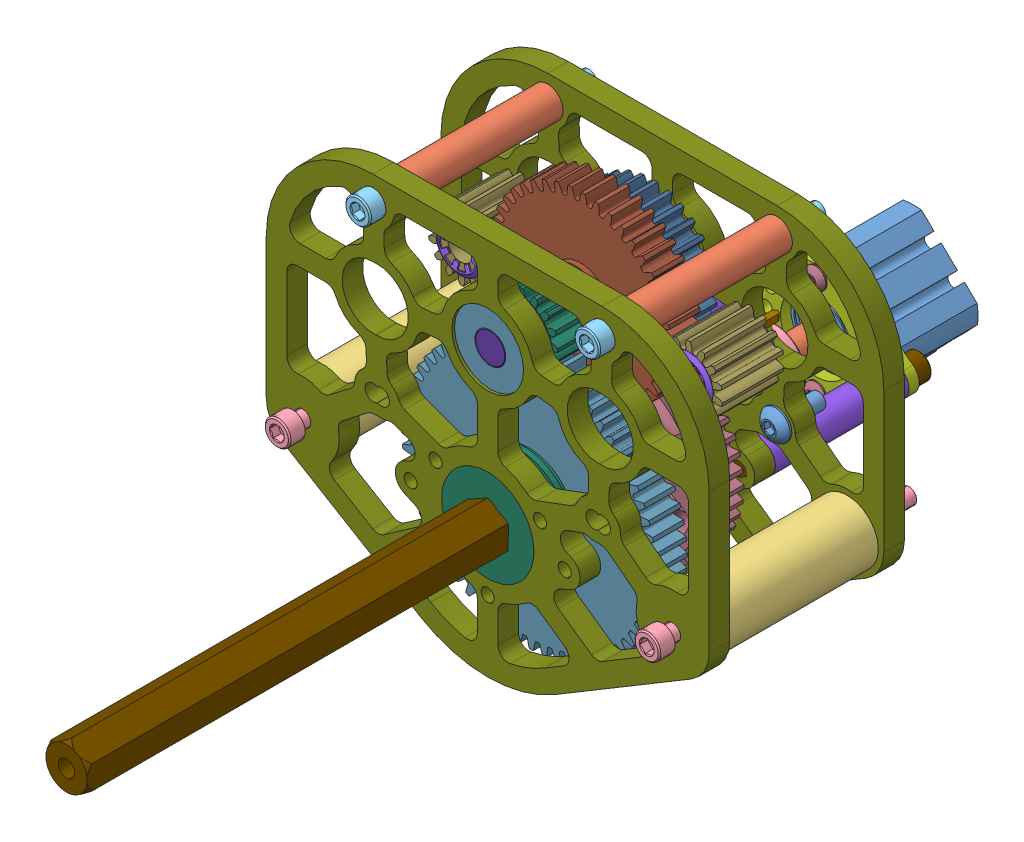
SolidWorks assembly 217-3423-STEP, configuration Default. Lengths in mm.
Overall size (138.74 141.15 261.84).
65 component instances, 41 part files, 0 mates.
Components (placement in the parent):
- 217-2778-001 Rev2_NCQ8A075-050M-1: 217-2778-001 Rev2_NCQ8A075-050M [Default] at (0 -47.0408 -61.087) x (-0.724709 0.689055 0) z (0 0 1) size (31.75 33.34 52.54)
  - 217-2778-NCQ8A075-050M_NCQ8 Tube_075A-1: 217-2778-NCQ8A075-050M_NCQ8 Tube_075A [Default] at origin size (31.75 33.34 26.92)
  - 217-2778-NCQ8A075-050M_NCQ8 Rod_075M-1: 217-2778-NCQ8A075-050M_NCQ8 Rod_075M [Default] at (0 0 3.8126) x (-1 0 0) z (0 0 1) size (18.95 18.95 35.27)
  - 217-2778-NCQ8A075-050M_Snap Ring_075-1: 217-2778-NCQ8A075-050M_Snap Ring_075 [Default] at (0 0 10.362) size (21 20.74 0.97)
- 217-3195-200 Rev1-1: 217-3195-200 Rev1 [Default] at (0 -47.0408 -22.8339) x (1 0 0) z (0 0 -1) size (20.44 19.56 22.68)
  - 217-3195-010 Rev1-1: 217-3195-010 Rev1 [Default] x (-1 0 0) z (0 0 1) size (19.61 11.78 22.68)
  - 217-3195-010 Rev1-2: 217-3195-010 Rev1 [Default] at origin size (19.61 11.78 22.68)
  - 217-2778-NCQ8A075-050M_1032_Nut_90545A111-1: 217-2778-NCQ8A075-050M_1032_Nut_90545A111 [Default] at (0 0 2.5527) x (-0.5 0.866025 0) z (0 0 1) size (9.53 11 3.39)
  - 91251A107_91251A107-1: 91251A107_91251A107 [Default] at (-7.4168 -4.9375 -0.635) x (1 0 0) z (0 -1 0) size (4.65 4.65 10.79)
  - 91251A107_91251A107-2: 91251A107_91251A107 [Default] at (7.4168 4.9375 -0.635) x (-0.837169 0 -0.546944) z (0 1 0) size (4.65 4.65 10.79)
- 217-3423-005 Rev1-1: 217-3423-005 Rev1 [Default] at (0 -47.0408 -46.0375) size (57.15 38.1 3.17)
- 217-3423-006 Rev1-1: 217-3423-006 Rev1 [Default] at (23.8125 -47.0408 -23.8125) x (0 0 1) z (0.999923 -0.012371 0) size (41.27 9.53 9.53)
- 217-3423-008 Rev1-1: 217-3423-008 Rev1 [Default] at (0 -47.0408 -11.5182) x (0 1 0) z (0 0 1) size (7.14 7.14 57.15)
- 217-3423-009 Rev3-1: 217-3423-009 Rev3 [Default] at (0 -47.0408 32.0872) x (-1 0 0) z (0 0 1) size (26.99 26.99 12.7)
- 217-3423-006 Rev1-2: 217-3423-006 Rev1 [Default] at (-23.8125 -47.0408 -23.8125) x (0 0 1) z (-0.442788 -0.896626 0) size (41.27 9.53 9.53)
- 217-3489-1: 217-3489 [Default] at (0 -47.0408 -16.3887) x (0 0 1) z (0.218426 -0.975853 0) size (4.77 12.7 12.7)
- 217-2428-027 Rev1_97414A630-1: 217-2428-027 Rev1_97414A630 [Default] at (0 -47.0408 -19.0874) x (0 0 1) z (-0.952629 0.304134 0) size (0.64 5.89 7.9)
- SBS1_SBS-0632-0250-1: SBS1_SBS-0632-0250 [Default] at (0 -31.5468 -42.5958) x (0 0 -1) z (0.950975 0.309268 0) size (8.57 6.68 6.65)
- SBS1_SBS-0632-0250-2: SBS1_SBS-0632-0250 [Default] at (0 -62.5348 -42.5958) x (0 0 -1) z (0.950975 0.309268 0) size (8.57 6.68 6.65)
- 217-2733-1: 217-2733 [Default] at (0 0 4.7625) x (0 0 -1) z (0.79471 -0.606989 0) size (7.11 24.61 24.61)
- 217-2733-2: 217-2733 [Default] at (0 0 49.2125) x (0 0 1) z (-0.575096 -0.818086 0) size (7.11 24.61 24.61)
- 217-2734-1: 217-2734 [Default] at (0 -47.0408 57.15) x (-0.033107 -0.999452 0) z (0.999452 -0.033107 0) size (31.12 7.94 31.12)
- 217-2734-2: 217-2734 [Default] at (0 -47.0408 39.6557) x (-0.405868 -0.913932 0) z (-0.913932 0.405868 0) size (31.12 7.94 31.12)
- 217-2743-1: 217-2743 [Default] at (0 -47.0408 7.9057) x (0 0 -1) z (0.947967 0.31837 0) size (7.94 28.58 28.58)
- 217-2731-1: 217-2731 [Default] at (0 -47.0408 3.175) x (-0.539745 -0.841828 0) z (0.841828 -0.539745 0) size (31.12 7.94 31.12)
- 217-3421-007 Rev1-1: 217-3421-007 Rev1 [Default] at (23.8125 -47.0408 -47.625) x (0 0 1) z (0.593474 0.804853 0) size (55.85 7.92 7.92)
- 217-3421-007 Rev1-2: 217-3421-007 Rev1 [Default] at (-23.8125 -47.0408 -47.625) x (0 0 1) z (-0.971026 -0.238972 0) size (55.85 7.92 7.92)
- 217-3421-009 Rev1-1: 217-3421-009 Rev1 [Default] at (35.4115 -29.21 3.175) x (0 0 -1) z (0.987344 0.158596 0) size (15.78 9.26 9.25)
- 217-3421-009 Rev1-2: 217-3421-009 Rev1 [Default] at (-35.4115 -29.21 3.175) x (0 0 -1) z (0.987344 0.158596 0) size (15.78 9.26 9.25)
- 217-3421-010 Rev1-1: 217-3421-010 Rev1 [Default] at (57.15 -47.0408 -3.175) x (0.898322 -0.439338 0) z (0.439338 0.898322 0) size (9.53 6.13 11)
- 217-3421-010 Rev1-2: 217-3421-010 Rev1 [Default] at (-57.15 -47.0408 -3.175) x (0.982822 -0.184556 0) z (0.184556 0.982822 0) size (9.53 6.13 11)
- 217-3421-011 Rev2_97633A200-1: 217-3421-011 Rev2_97633A200 [Default] at (0 -47.0408 -5.2388) x (0 0 -1) z (0.95045 -0.310879 0) size (0.89 16.1 14.34)
- 217-3422-006 Rev1-1: 217-3422-006 Rev1 [Default] at (57.15 -47.0408 60.325) x (0 0 -1) z (-0.733896 -0.679262 0) size (81.25 7.92 7.92)
- 217-3422-006 Rev1-2: 217-3422-006 Rev1 [Default] at (-57.15 -47.0408 60.325) x (0 0 -1) z (0.0516 0.998668 0) size (81.25 7.92 7.92)
- 217-3423-012 Rev1-1: 217-3423-012 Rev1 [Default] at (35.4115 21.59 57.15) x (0 0 -1) z (0.651943 -0.758268 0) size (71.73 7.92 7.92)
- 217-3423-012 Rev1-2: 217-3423-012 Rev1 [Default] at (-35.4115 21.59 57.15) x (0 0 -1) z (0.658015 -0.753004 0) size (71.73 7.92 7.92)
- 217-3423-014 Rev1-1: 217-3423-014 Rev1 [Default] at (-13.4938 -47.0408 32.0872) x (0 0.867283 -0.497815) z (-1 0 0) size (4.65 4.65 26.79)
- 217-3423-016 Rev1-1: 217-3423-016 Rev1 [Default] at (0 -65.6939 -4.7625) x (0 0 1) z (-0.596583 -0.802551 0) size (11.03 9.26 9.25)
- 217-3423-016 Rev1-2: 217-3423-016 Rev1 [Default] at (-16.1541 -37.7142 -4.7625) x (0 0 1) z (-0.596583 -0.802551 0) size (11.03 9.26 9.25)
- 217-3423-016 Rev1-3: 217-3423-016 Rev1 [Default] at (16.1541 -37.7142 -4.7625) x (0 0 1) z (-0.596583 -0.802551 0) size (11.03 9.26 9.25)
- 217-2614-002_98430A132-1: 217-2614-002_98430A132 [Default] at (35.4115 -3.81 9.9695) x (0 0 1) z (-0.864814 -0.502092 0) size (1.2 14.83 14.83)
- 217-2614-002_98430A132-2: 217-2614-002_98430A132 [Default] at (35.4115 -3.81 31.1531) x (0 0 -1) z (0.980787 -0.195081 0) size (1.2 14.83 14.83)
- 217-2614-002_98430A132-3: 217-2614-002_98430A132 [Default] at (-35.4115 -3.81 31.1531) x (0 0 -1) z (-0.821319 -0.570469 0) size (1.2 14.83 14.83)
- 217-2614-002_98430A132-4: 217-2614-002_98430A132 [Default] at (-35.4115 -3.81 9.9695) x (0 0 1) z (-0.844607 -0.535387 0) size (1.2 14.83 14.83)
- 217-2761-001 rev1-1: 217-2761-001 rev1 [Default] at (-35.4115 -0.01 12.925) size (2 2 20)
- 217-2761-001 rev1-2: 217-2761-001 rev1 [Default] at (35.4115 -0.01 12.925) size (2 2 20)
- 217-3210-001 Rev1_30t-1: 217-3210-001 Rev1_30t [Default] at (0 0 11.0871) x (0.988842 0.148971 0) z (0 0 1) size (41.01 41.12 12.65)
- 217-3215-001 Rev1_42t-1: 217-3215-001 Rev1_42t [Default] at (0 0 23.7363) x (0.8078 -0.589457 0) z (0 0 1) size (56.22 56.3 12.65)
- 217-3414-001 Rev1_14t Steel Pinion-1: 217-3414-001 Rev1_14t Steel Pinion [Default] at (-35.4115 -3.81 20.5613) x (0.914095 -0.405501 0) z (0 0 1) size (20.32 20.6 19.05)
- 217-3414-001 Rev1_14t Steel Pinion-2: 217-3414-001 Rev1_14t Steel Pinion [Default] at (35.4115 -3.81 20.5613) x (0.999225 0.039352 0) z (0 0 1) size (20.32 20.6 19.05)
- 217-3418-001 Rev2_44t-1: 217-3418-001 Rev2_44t [Default] at (0 -47.0408 11.922) x (0.876071 -0.482182 0) z (0 0 1) size (58.67 58.67 9.53)
- 217-3420-001 Rev2_60t-1: 217-3420-001 Rev2_60t [Default] at (0 -47.0408 39.6082) x (-0.829017 -0.559223 0) z (0 0 -1) size (78.95 78.95 9.53)
- 217-3100-001_14t-1: 217-3100-001_14t [Default] at (0 0 39.5859) x (0.526969 0.849885 0) z (0 0 1) size (20.32 20.6 12.7)
- 217-3423-001 Rev1_Default_As Machined_-1: 217-3423-001 Rev1_Default_As Machined_ [Default] at origin size (136.86 116.89 6.35)
- 217-3423-001 Rev1_Default_As Machined_-2: 217-3423-001 Rev1_Default_As Machined_ [Default] at (0 0 53.975) x (-1 0 0) z (0 0 -1) size (136.86 116.89 6.35)
- 217-3423-002 Rev1-1: 217-3423-002 Rev1 [Default] at (0 0 26.9875) x (0.576816 0.816874 0) z (0 0 1) size (11 9.53 58.74)
- 217-3423-003 Rev1-1: 217-3423-003 Rev1 [Default] at (0 -47.0408 25.7651) x (0 -1 0) z (0 0 1) size (18.33 15.88 194.69)
- 217-3423-004 Rev1-1: 217-3423-004 Rev1 [Default] at (0 -47.0408 3.556) size (19.05 19.05 0.76)
- 217-3423-010 Rev1-1: 217-3423-010 Rev1 [Default] at (35.4115 21.59 26.9875) x (-0.522062 0.852908 0) z (0 0 1) size (9.53 9.53 47.62)
- 217-3423-010 Rev1-2: 217-3423-010 Rev1 [Default] at (-35.4115 21.59 26.9875) size (9.53 9.53 47.62)
- 217-3423-011 Rev1-1: 217-3423-011 Rev1 [Default] at (-57.15 -47.0408 26.9875) size (19.13 19.13 53.98)
- 217-3423-011 Rev1-2: 217-3423-011 Rev1 [Default] at (57.15 -47.0408 26.9875) x (0.850589 -0.525831 0) z (0 0 1) size (19.13 19.13 53.98)
- 217-3256-001 Rev1-1: 217-3256-001 Rev1 [Default] at (0 0 31.6484) x (0.524203 -0.851594 0) z (0 0 1) size (15.88 15.88 3.17)
- 217-3256-001 Rev1-2: 217-3256-001 Rev1 [Default] at (0 0 47.625) x (-0.224279 -0.974525 0) z (0 0 1) size (15.88 15.88 3.17)
- 217-3257-001 Rev1-1: 217-3257-001 Rev1 [Default] at (0 -47.0408 48.4188) size (19.5 19.5 1.59)
